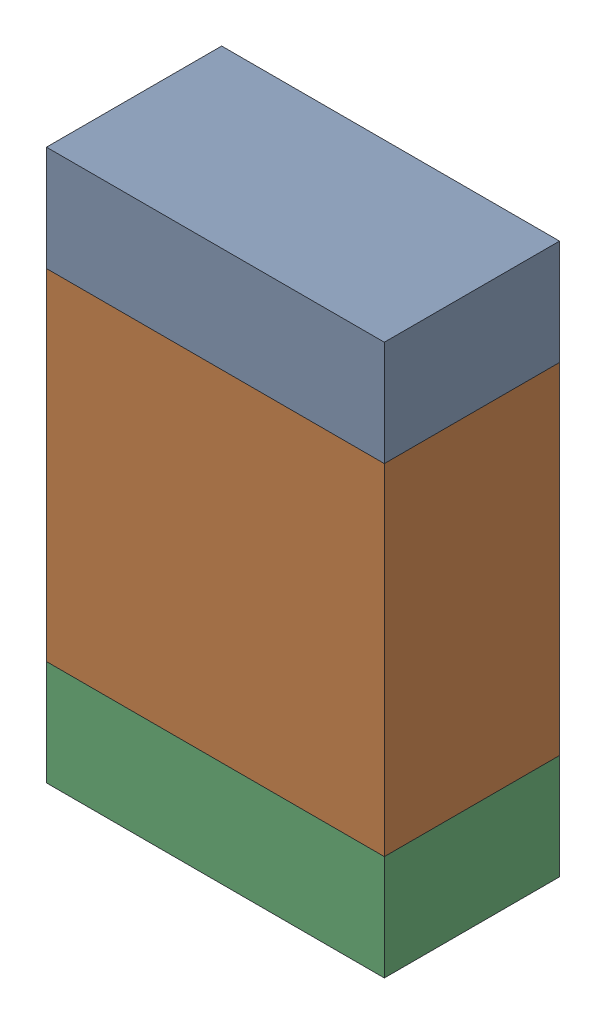
SolidWorks assembly R9-1, configuration Default. Lengths in mm.
Overall size (1.35 2.2 0.7).
6 component instances, 2 part files, 0 mates.
Components (placement in the parent):
- 959207304-1-1: 959207304-1 [Default] at (77.5971 95.5049 0) size (1.35 0.42 0.7)
  - Extruded-39-1: Extruded-39 [Default] at origin size (1.35 0.42 0.7)
- 959207440-1-1: 959207440-1 [Default] at (77.5971 94.6149 0) size (1.35 1.36 0.7)
  - Extruded-40-1: Extruded-40 [Default] at origin size (1.35 1.36 0.7)
- 959207304-1-2: 959207304-1 [Default] at (77.5971 93.7249 0) size (1.35 0.42 0.7)
  - Extruded-39-1: Extruded-39 [Default] at origin size (1.35 0.42 0.7)
